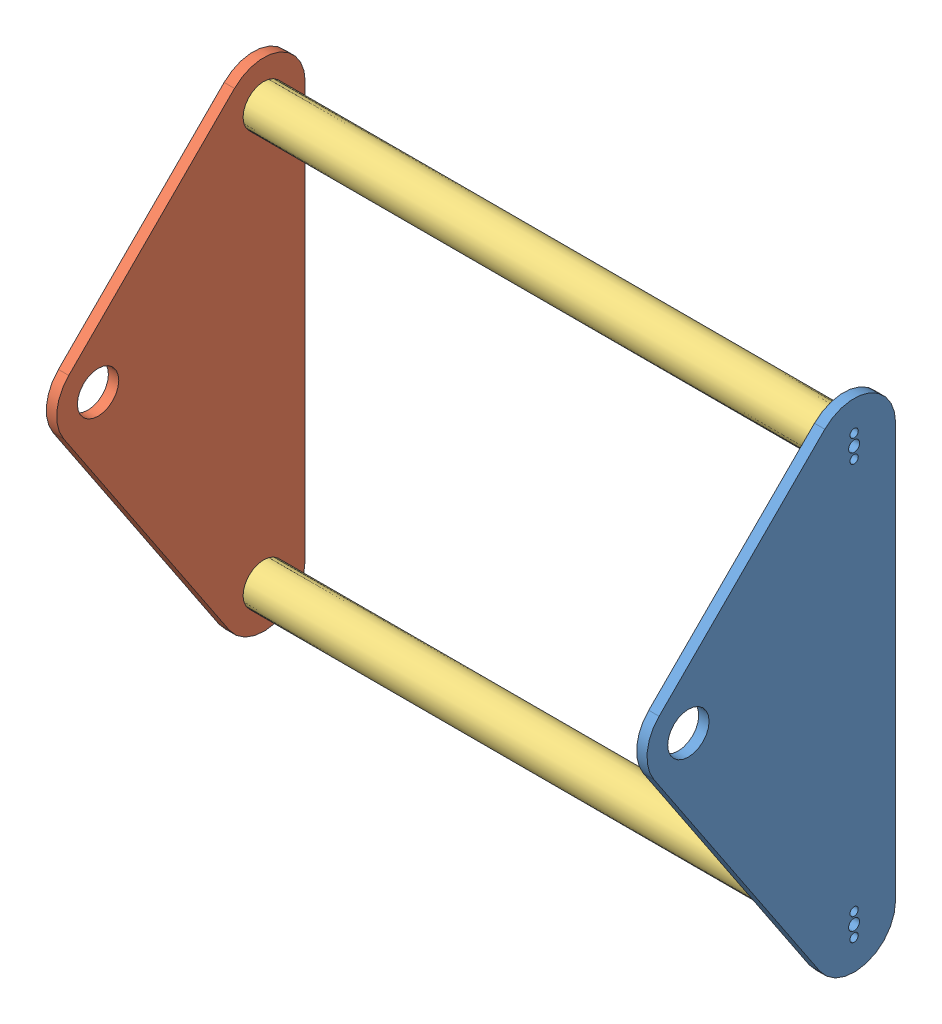
SolidWorks assembly 2018-301-A, configuration Default. Lengths in mm.
Overall size (368.3 304.8 152.4).
4 component instances, 3 part files, 7 mates.
Components (placement in the parent):
- 2018-301-D001-1: 2018-301-D001 [Default] at (177.8 0 0) size (6.35 304.8 152.4)
- Mirror2018-301-D001-2: Mirror2018-301-D001 [Default] at (-177.8 0 0) x (-1 0 0) z (0 0 -1) size (6.35 304.8 152.4)
- 2018-301-D002-2: 2018-301-D002 [Default] at (0 101.6 -101.6) x (0 -0.477133 -0.878831) z (1 0 0) size (25.4 25.4 355.6)
- 2018-301-D002-1: 2018-301-D002 [Default] at (0 -152.4 -101.6) x (0 -0.477133 -0.878831) z (1 0 0) size (25.4 25.4 355.6)
Mates (geometry in assembly coordinates):
- Coincident1: coincident aligned: plane of 2018-301-D001-1 through (177.8 0 0) normal (0 1 0); plane of assembly through (0 0 0) normal (0 1 0)
- Coincident2: coincident aligned: plane of 2018-301-D001-1 through (177.8 0 0) normal (0 0 1); plane of assembly through (0 0 0) normal (0 0 1)
- Distance1: distance = 177.8 mm aligned: plane of assembly through (0 0 0) normal (1 0 0); plane of 2018-301-D001-1 through (177.8 0 0) normal (1 0 0)
- Concentric1: concentric anti-aligned: cylinder of 2018-301-D001-1 through (184.15 101.6 -101.6) axis (1 0 0) radius 3.3782; cylinder of 2018-301-D002-2 through (177.8 101.6 -101.6) axis (-1 0 0) radius 12.7
- Coincident4: coincident anti-aligned: plane of 2018-301-D001-1 through (177.8 0 0) normal (-1 0 0); plane of 2018-301-D002-2 through (177.8 101.6 -101.6) normal (1 0 0)
- Concentric2: concentric anti-aligned: cylinder of 2018-301-D001-1 through (184.15 -152.4 -101.6) axis (1 0 0) radius 3.3782; cylinder of 2018-301-D002-1 through (177.8 -152.4 -101.6) axis (-1 0 0) radius 12.7
- Coincident5: coincident anti-aligned: plane of 2018-301-D001-1 through (177.8 0 0) normal (-1 0 0); plane of 2018-301-D002-1 through (177.8 -152.4 -101.6) normal (1 0 0)
